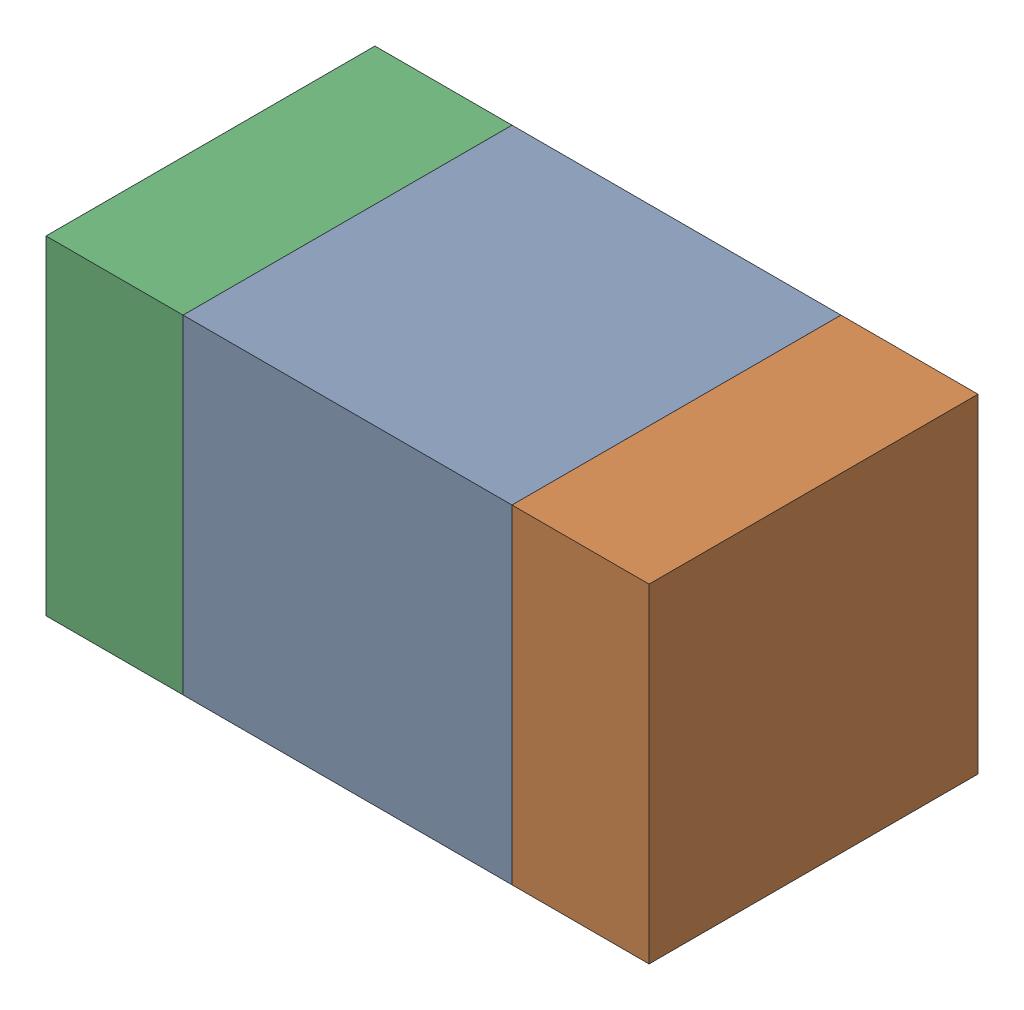
SolidWorks assembly C304_2PCB, configuration Default. Lengths in mm.
Overall size (1.1 0.6 0.6).
6 component instances, 2 part files, 0 mates.
Components (placement in the parent):
- 761606048-1: 761606048 [Default] at (143.4 85.6 0) size (0.6 0.6 0.6)
  - Extruded_9-1: Extruded_9 [Default] at origin size (0.6 0.6 0.6)
- 854785160-1: 854785160 [Default] at (143.825 85.6 0) size (0.25 0.6 0.6)
  - Extruded_19-1: Extruded_19 [Default] at origin size (0.25 0.6 0.6)
- 854785160-2: 854785160 [Default] at (142.975 85.6 0) size (0.25 0.6 0.6)
  - Extruded_19-1: Extruded_19 [Default] at origin size (0.25 0.6 0.6)
